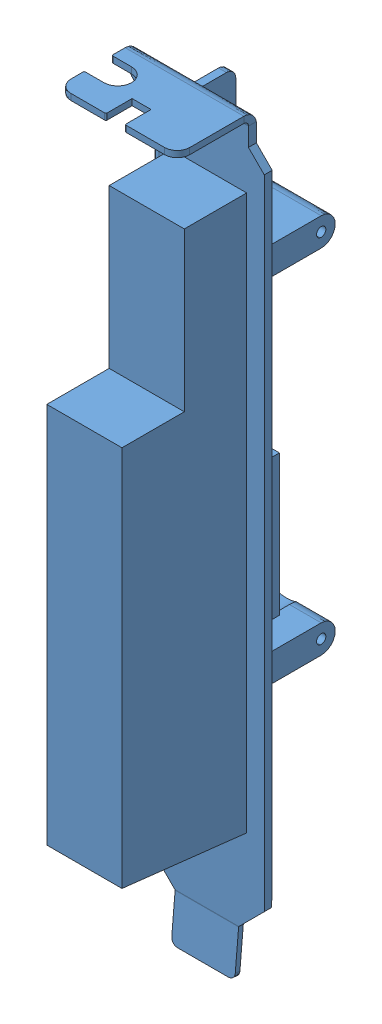
SolidWorks assembly Assem1, configuration Default. Lengths in mm.
Overall size (21.59 121 35.52).
2 component instances, 2 part files, 3 mates.
Components (placement in the parent):
- pcie-bracket-1p27mm-1: pcie-bracket-1p27mm [默认] at (37.1719 119.8921 91.0256) size (21.59 121 35.52)
- mmcx-gang-1: mmcx-gang [Default] at (51.6174 52.1381 91.0256) x (0 -1 0) z (0 0 1) size (30 8 10)
Mates (geometry in assembly coordinates):
- Coincident1: coincident anti-aligned: plane of pcie-bracket-1p27mm-1 through (37.1719 119.8921 91.0256) normal (0 0 1); plane of mmcx-gang-1 through (51.6174 52.1381 91.0256) normal (0 0 -1)
- Parallel1: parallel aligned: plane of pcie-bracket-1p27mm-1 through (54.6169 38.2181 91.0256) normal (0 -1 0); plane of mmcx-gang-1 through (47.6174 37.1381 101.0256) normal (0 -1 0)
- Coincident4: coincident aligned: plane of pcie-bracket-1p27mm-1 through (48.8569 67.1381 111.0266) normal (0 1 0); plane of mmcx-gang-1 through (47.6174 67.1381 101.0256) normal (0 1 0)
